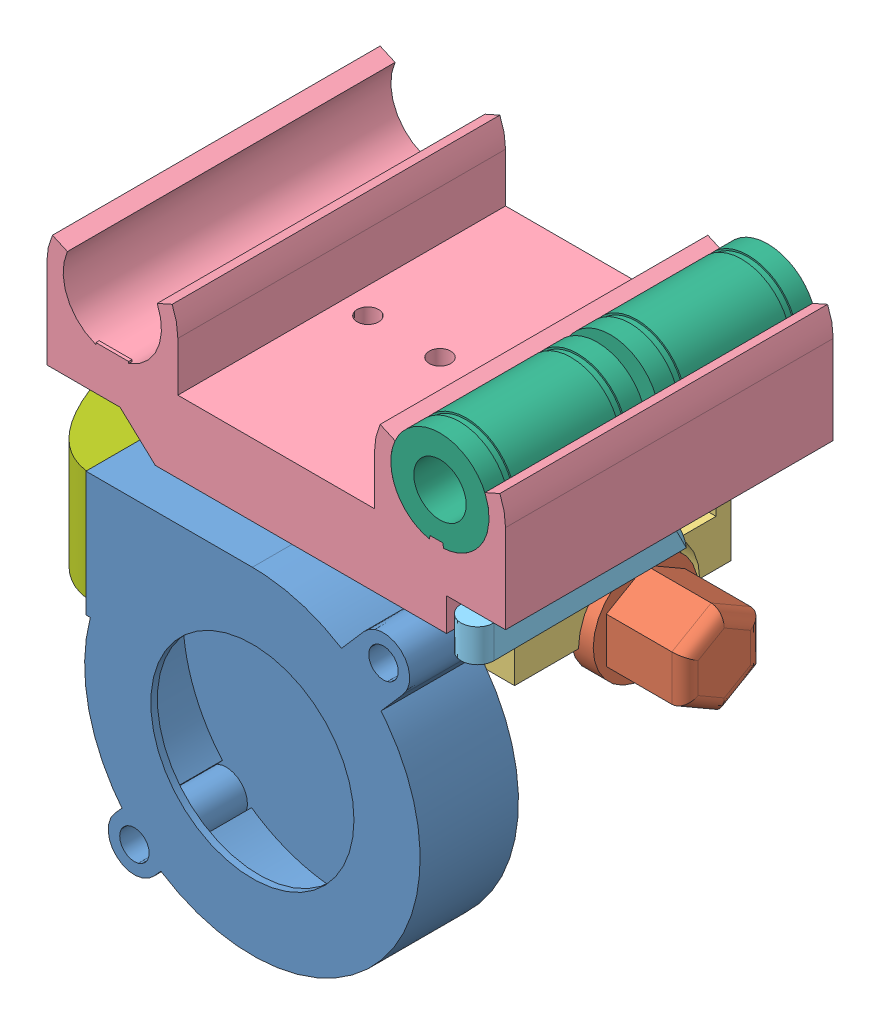
SolidWorks assembly #montagem2, configuration Valor predeterminado. Lengths in mm.
Overall size (79.92 84 52.58).
8 component instances, 7 part files, 19 mates.
Components (placement in the parent):
- Cooler (50x50x15)-1: Cooler (50x50x15) [Valor predeterminado] at (8.0332 -5.5942 32.3358) size (51.8 53 15)
- hotend-1: hotend [Valor predeterminado] at (-17.6261 9.4058 13.3358) x (0 0 -1) z (0 -1 0) size (24.7 79 24.7)
- suporte_ferramenta_impressao-1: suporte_ferramenta_impressao [Valor predeterminado] at (20.0332 31.4058 22.6358) x (0 0 -1) z (0 -1 0) size (40.6 64 62.5)
- X_carriage_multitool-1: X_carriage_multitool [Valor predeterminado] at (11.9575 31.4058 22.6358) x (0 1 0) z (0 0 -1) size (22.57 70 50)
- alavanca-1: alavanca [Valor predeterminado] at (42.4575 31.4058 22.6358) x (0.00851 0 0.999964) z (0 -1 0) size (35.22 11.76 5)
- linear bearing-2: linear bearing [Valor predeterminado] at (36.9575 44.9058 -2.3642) x (1 0 0) z (0 1 0) size (15 24 15)
- linear bearing-3: linear bearing [Valor predeterminado] at (36.9575 44.9058 23.6358) x (1 0 0) z (0 1 0) size (15 24 15)
- fan_duct-1: fan_duct [Valor predeterminado] at (-2.3668 10.5558 39.8358) x (0 -1 0) z (-1 0 0) size (36.4 22.83 29.37)
Mates (geometry in assembly coordinates):
- Paralelo1: parallel anti-aligned: plane of Cooler (50x50x15)-1 through (8.0332 -5.5942 47.3358) normal (0 0 1); plane of hotend-1 through (-27.9668 -2.5942 5.3358) normal (0 0 -1)
- Paralelo2: parallel aligned: plane of Cooler (50x50x15)-1 through (-17.3668 20.0558 47.3358) normal (0 1 0); plane of hotend-1 through (-27.9668 13.4058 21.3358) normal (0 1 0)
- Concêntrico1: concentric aligned: cylinder of suporte_ferramenta_impressao-1 through (23.0332 9.4058 13.3358) axis (1 0 0) radius 5.8; cylinder of hotend-1 through (34.0332 9.4058 13.3358) axis (1 0 0) radius 5.5
- Paralelo3: parallel anti-aligned: plane of Cooler (50x50x15)-1 through (-17.3668 20.0558 47.3358) normal (0 1 0); plane of suporte_ferramenta_impressao-1 through (20.0332 24.4058 22.6358) normal (0 -1 0)
- Coincidente7: coincident anti-aligned: plane of hotend-1 through (30.5332 9.4058 7.8358) normal (-1 0 0); plane of suporte_ferramenta_impressao-1 through (30.5332 9.4058 13.3358) normal (1 0 0)
- Concêntrico3: concentric anti-aligned: cylinder of Cooler (50x50x15)-1 through (28.0332 17.4058 47.3358) axis (0 0 -1) radius 2.25; cylinder of suporte_ferramenta_impressao-1 through (28.0332 17.4058 22.3358) axis (0 0 1) radius 1.65
- Coincidente8: coincident anti-aligned: plane of Cooler (50x50x15)-1 through (8.0332 -5.5942 32.3358) normal (0 0 -1); plane of suporte_ferramenta_impressao-1 through (23.0332 24.4058 32.3358) normal (0 0 1)
- Coincidente9: coincident anti-aligned: plane of suporte_ferramenta_impressao-1 through (20.0332 31.4058 22.6358) normal (0 1 0); plane of X_carriage_multitool-1 through (46.9575 31.4058 -2.3642) normal (0 -1 0)
- Largura2: width anti-aligned: plane of suporte_ferramenta_impressao-1 through (33.0332 24.4058 5.3358) normal (0 0 -1); plane of suporte_ferramenta_impressao-1 through (33.0332 24.4058 39.9358) normal (0 0 1); plane of X_carriage_multitool-1 through (37.9575 26.4058 5.1358) normal (0 0 1); plane of X_carriage_multitool-1 through (37.9575 26.4058 40.1358) normal (0 0 -1)
- DistânciaLimite1: limit distance = 8.5 mm: point of X_carriage_multitool-1; point of suporte_ferramenta_impressao-1
- Concêntrico4: concentric anti-aligned: cylinder of X_carriage_multitool-1 through (42.4575 44.4058 22.6358) axis (0 -1 0) radius 1.65; cylinder of alavanca-1 through (42.4575 26.4058 22.6358) axis (0 1 0) radius 1.65
- Coincidente11: coincident anti-aligned: plane of X_carriage_multitool-1 through (46.9575 31.4058 -2.3642) normal (0 -1 0); plane of alavanca-1 through (42.6703 31.4058 47.6349) normal (0 1 0)
- Concêntrico5: concentric anti-aligned: cylinder of X_carriage_multitool-1 through (36.9575 44.9058 -2.3642) axis (0 0 1) radius 7.5; cylinder of linear bearing-2 through (36.9575 44.9058 -2.3642) axis (0 0 -1) radius 7.5
- Coincidente12: coincident aligned: plane of X_carriage_multitool-1 through (36.9575 44.9058 -2.3642) normal (0 0 -1); plane of linear bearing-2 through (40.9575 44.9058 -2.3642) normal (0 0 -1)
- Concêntrico6: concentric anti-aligned: cylinder of X_carriage_multitool-1 through (36.9575 44.9058 -2.3642) axis (0 0 1) radius 7.5; cylinder of linear bearing-3 through (36.9575 44.9058 23.6358) axis (0 0 -1) radius 7.5
- Coincidente13: coincident aligned: plane of X_carriage_multitool-1 through (36.9575 44.9058 47.6358) normal (0 0 1); plane of linear bearing-3 through (44.4575 44.9058 47.6358) normal (0 0 1)
- Largura3: width anti-aligned: plane of fan_duct-1 through (-17.3668 18.9558 33.4358) normal (0 0 -1); plane of fan_duct-1 through (-17.3668 18.9558 46.2358) normal (0 0 1); plane of Cooler (50x50x15)-1 through (8.0332 -5.5942 33.3358) normal (0 0 1); plane of Cooler (50x50x15)-1 through (8.0332 -5.5942 46.3358) normal (0 0 -1)
- Largura4: width anti-aligned: plane of fan_duct-1 through (-17.3668 18.9558 46.2358) normal (0 1 0); plane of fan_duct-1 through (-17.3668 2.1558 46.2358) normal (0 -1 0); plane of Cooler (50x50x15)-1 through (-17.3668 2.0558 47.3358) normal (0 1 0); plane of Cooler (50x50x15)-1 through (-17.3668 19.0558 47.3358) normal (0 -1 0)
- Coincidente14: coincident: plane of Cooler (50x50x15)-1 through (-17.3668 20.0558 47.3358) normal (-1 0 0); line of fan_duct-1 through (-17.3668 2.1558 46.2358) axis (0 1 0)
